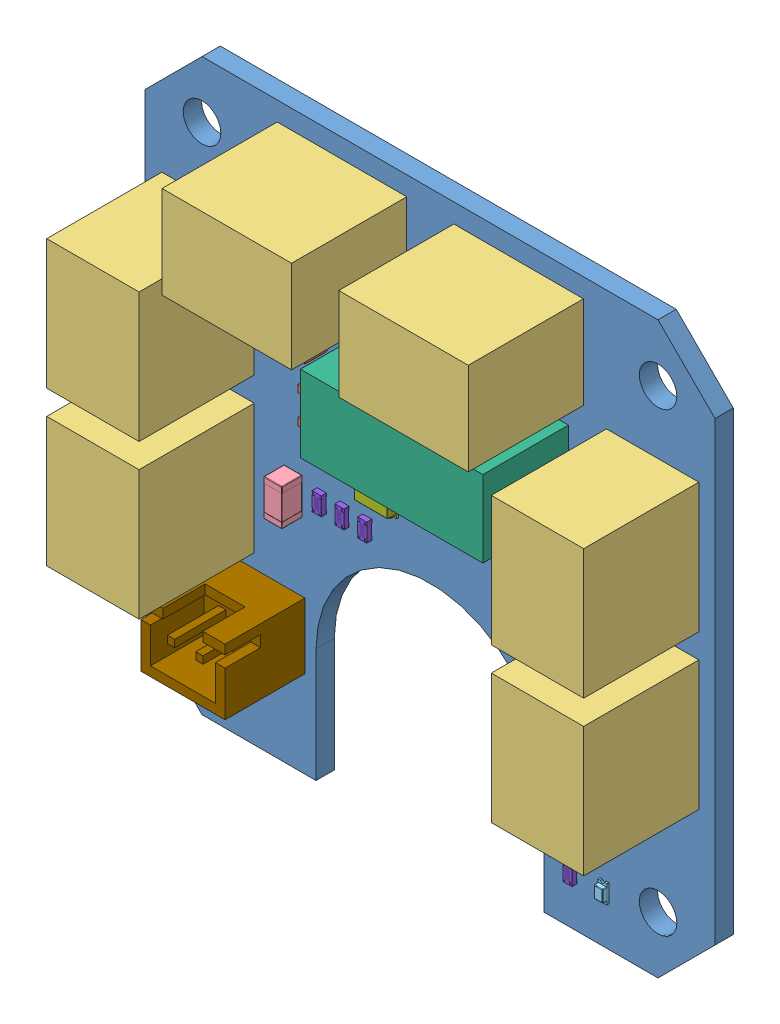
SolidWorks assembly Power Board, configuration 預設. Lengths in mm.
Overall size (50 50 18.8).
18 component instances, 9 part files, 0 mates.
Components (placement in the parent):
- BoardOutline_Power Board-1: BoardOutline_Power Board [預設] at origin size (50 50 1.6)
- JST_XH_B4B-XH-A_4_Pin_1-1: JST_XH_B4B-XH-A_4_Pin_1 [預設] at (15.527 32.037 0) x (0 1 0) z (0 0 -1) size (12.4 5.75 10.4)
- 691213510002_2_Pin_1-1: 691213510002_2_Pin_1 [預設] at (33 44.5 1.6) size (11.36 8.1 15.2)
- 691213510002_2_Pin_1-2: 691213510002_2_Pin_1 [預設] at (17.5 44.5 1.6) size (11.36 8.1 15.2)
- 691213510002_2_Pin_1-3: 691213510002_2_Pin_1 [預設] at (44.5 34 1.6) x (0 1 0) z (0 0 1) size (11.36 8.1 15.2)
- 691213510002_2_Pin_1-4: 691213510002_2_Pin_1 [預設] at (44.5 20.5 1.6) x (0 1 0) z (0 0 1) size (11.36 8.1 15.2)
- 691213510002_2_Pin_1-5: 691213510002_2_Pin_1 [預設] at (5.5 20.5 1.6) x (0 1 0) z (0 0 1) size (11.36 8.1 15.2)
- 691213510002_2_Pin_1-6: 691213510002_2_Pin_1 [預設] at (5.5 34 1.6) x (0 1 0) z (0 0 1) size (11.36 8.1 15.2)
- CAP_1206_3216_-_1.8MM_Capacitor_1-1: CAP_1206_3216_-_1.8MM_Capacitor_1 [預設] at (13 21 1.6) x (0 -1 0) z (0 0 1) size (3.2 1.6 1.8)
- LED_0603_1608_BLUE_LED_1-1: LED_0603_1608_BLUE_LED_1 [預設] at (40.292 4.28 1.6) x (0 -1 0) z (0 0 1) size (1.6 0.8 0.53)
- 356810_3568-10_1-1: 356810_3568-10_1 [預設] at (24.275 33.1 1.6) size (16 6.73 12.6)
- SOT-23-3_SINGLE_N-MOSFET_1-1: SOT-23-3_SINGLE_N-MOSFET_1 [預設] at (21 25 1.6) size (3.01 2.84 1.18)
- RES_0603_1608_RF_Resistor_1-1: RES_0603_1608_RF_Resistor_1 [預設] at (17.5 21.5 1.6) x (0 -1 0) z (0 0 1) size (1.6 0.8 0.45)
- RES_0603_1608_RF_Resistor_1-2: RES_0603_1608_RF_Resistor_1 [預設] at (19.5 21.5 1.6) x (0 1 0) z (0 0 1) size (1.6 0.8 0.45)
- RES_0603_1608_RF_Resistor_1-3: RES_0603_1608_RF_Resistor_1 [預設] at (15.5 21.5 1.6) x (0 -1 0) z (0 0 1) size (1.6 0.8 0.45)
- RES_0603_1608_RF_Resistor_1-4: RES_0603_1608_RF_Resistor_1 [預設] at (21 28 1.6) size (1.6 0.8 0.45)
- RES_0603_1608_RF_Resistor_1-5: RES_0603_1608_RF_Resistor_1 [預設] at (37.498 4.407 1.6) x (0 1 0) z (0 0 1) size (1.6 0.8 0.45)
- JST_XH_B2B-XH-A_2_Pin_1-1: JST_XH_B2B-XH-A_2_Pin_1 [預設] at (10.325 11 1.6) size (7.4 5.75 10.4)
